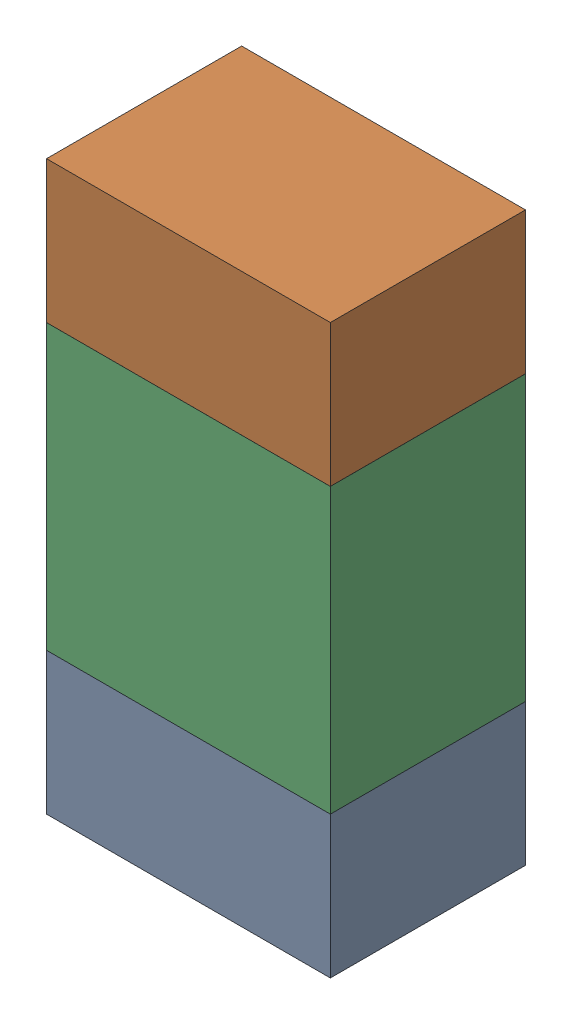
SolidWorks assembly R5, configuration ﾃﾞﾌｫﾙﾄ. Lengths in mm.
Overall size (0.8 1.6 0.55).
6 component instances, 2 part files, 0 mates.
Components (placement in the parent):
- 689261784-1: 689261784 [ﾃﾞﾌｫﾙﾄ] at (15.2499 24.1501 0) size (0.8 0.4 0.55)
  - Extruded_34-1: Extruded_34 [ﾃﾞﾌｫﾙﾄ] at origin size (0.8 0.4 0.55)
- 689261784-2: 689261784 [ﾃﾞﾌｫﾙﾄ] at (15.2499 25.3501 0) size (0.8 0.4 0.55)
  - Extruded_34-1: Extruded_34 [ﾃﾞﾌｫﾙﾄ] at origin size (0.8 0.4 0.55)
- 689261648-1: 689261648 [ﾃﾞﾌｫﾙﾄ] at (15.2499 24.75 0) size (0.8 0.8 0.55)
  - Extruded_33-1: Extruded_33 [ﾃﾞﾌｫﾙﾄ] at origin size (0.8 0.8 0.55)
